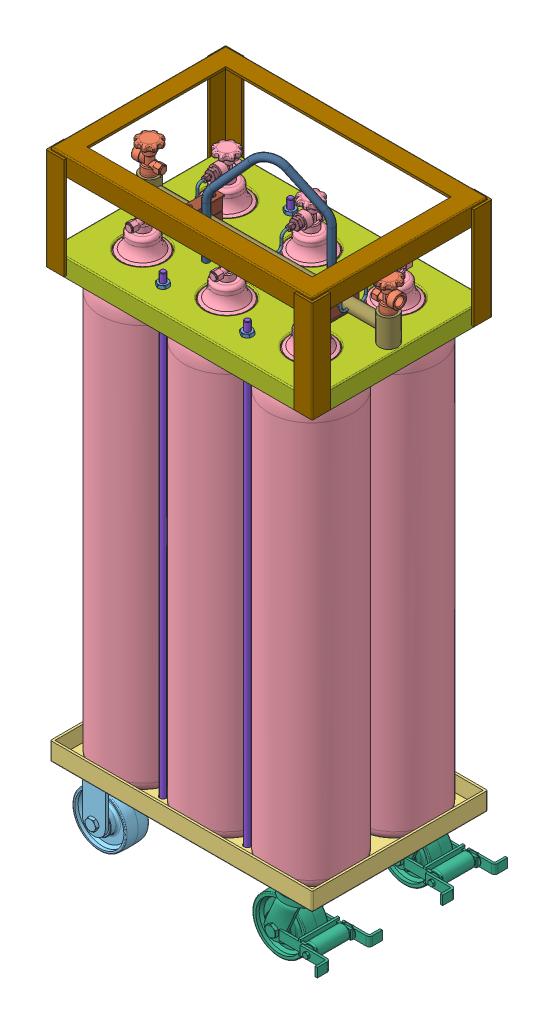
SolidWorks assembly GH2 6-Pack of K Bottles, configuration Default. Lengths in mm.
Overall size (889.45 1721.67 530.22).
43 component instances, 14 part files, 63 mates.
Components (placement in the parent):
- heavy hex jam nut_ai-1: heavy hex jam nut_ai [HHJNUT 0.6250-11-D-N] at (-117.475 1242.8474 177.8) x (1 0 0) z (0 1 0) size (26.97 31.15 9.68)
- heavy hex jam nut_ai-2: heavy hex jam nut_ai [HHJNUT 0.6250-11-D-N] at (117.475 1242.8474 177.8) x (1 0 0) z (0 1 0) size (26.97 31.15 9.68)
- heavy hex jam nut_ai-3: heavy hex jam nut_ai [HHJNUT 0.6250-11-D-N] at (117.475 1242.8474 -177.8) x (1 0 0) z (0 1 0) size (26.97 31.15 9.68)
- heavy hex jam nut_ai-4: heavy hex jam nut_ai [HHJNUT 0.6250-11-D-N] at (-117.475 1242.8474 -177.8) x (1 0 0) z (0 1 0) size (26.97 31.15 9.68)
- heavy hex jam nut_ai-5: heavy hex jam nut_ai [HHJNUT 0.6250-11-D-N] at (-117.475 -16.0274 177.8) x (1 0 0) z (0 -1 0) size (26.97 31.15 9.68)
- heavy hex jam nut_ai-6: heavy hex jam nut_ai [HHJNUT 0.6250-11-D-N] at (117.475 -16.0274 177.8) x (1 0 0) z (0 -1 0) size (26.97 31.15 9.68)
- heavy hex jam nut_ai-7: heavy hex jam nut_ai [HHJNUT 0.6250-11-D-N] at (117.475 -16.0274 -177.8) x (1 0 0) z (0 -1 0) size (26.97 31.15 9.68)
- heavy hex jam nut_ai-8: heavy hex jam nut_ai [HHJNUT 0.6250-11-D-N] at (-117.475 -16.0274 -177.8) x (1 0 0) z (0 -1 0) size (26.97 31.15 9.68)
- K Type Pressure Cylinder Valve-1: K Type Pressure Cylinder Valve [Default] at (333.375 -69.85 0) size (186.86 1361.63 197.95)
- Part15^GH2 6-Pack of K Bottles-1: Part15^GH2 6-Pack of K Bottles [Default] x (1 0 0) z (0 1 0) size (730.25 488.95 50.8) (virtual)
- K Type Pressure Cylinder GH2-1: K Type Pressure Cylinder GH2 [Default] at (234.95 -101.6 -117.475) x (0 0 1) z (-1 0 0) size (239.72 1361.76 239.72)
- K Type Pressure Cylinder GH2-5: K Type Pressure Cylinder GH2 [Default] at (234.95 -101.6 117.475) x (0 0 -1) z (1 0 0) size (239.72 1361.76 239.72)
- K Type Pressure Cylinder GH2-3: K Type Pressure Cylinder GH2 [Default] at (-234.95 -101.6 -117.475) x (0 0 1) z (-1 0 0) size (239.72 1361.76 239.72)
- K Type Pressure Cylinder GH2-4: K Type Pressure Cylinder GH2 [Default] at (-234.95 -101.6 117.475) x (0 0 -1) z (1 0 0) size (239.72 1361.76 239.72)
- K Type Pressure Cylinder GH2-2: K Type Pressure Cylinder GH2 [Default] at (0 -101.6 -117.475) x (0 0 1) z (-1 0 0) size (239.72 1361.76 239.72)
- K Type Pressure Cylinder GH2-6: K Type Pressure Cylinder GH2 [Default] at (0 -101.6 117.475) x (0 0 -1) z (1 0 0) size (239.72 1361.76 239.72)
- 2432T12_Extra-High-Capacity Viking Caster-1: 2432T12_Extra-High-Capacity Viking Caster [2432T12] at (-273.05 -123.825 168.275) x (1 0 0) z (0 1 0) size (158.75 127 193.67)
- 2432T55_Extra-High-Capacity Viking Caster-1: 2432T55_Extra-High-Capacity Viking Caster [2432T55] at (234.95 -123.825 174.625) x (1 0 0) z (0 1 0) size (241.3 180.97 193.67)
- 2432T55_Extra-High-Capacity Viking Caster-2: 2432T55_Extra-High-Capacity Viking Caster [2432T55] at (234.95 -123.825 -174.625) x (1 0 0) z (0 1 0) size (241.3 180.97 193.67)
- 2432T12_Extra-High-Capacity Viking Caster-2: 2432T12_Extra-High-Capacity Viking Caster [2432T12] at (-273.05 -123.825 -168.275) x (-1 0 0) z (0 1 0) size (158.75 127 193.67)
- Part16^GH2 6-Pack of K Bottles-1: Part16^GH2 6-Pack of K Bottles [Default] at (0 1226.82 0) x (-1 0 0) z (0 -1 0) size (730.25 488.95 50.8) (virtual)
- Part17^GH2 6-Pack of K Bottles-1: Part17^GH2 6-Pack of K Bottles [Default] at (117.475 1242.8474 177.8) x (1 0 0) z (0 1 0) size (15.88 15.88 1309.67) (virtual)
- Part17^GH2 6-Pack of K Bottles-2: Part17^GH2 6-Pack of K Bottles [Default] at (117.475 1242.8474 -177.8) x (1 0 0) z (0 1 0) size (15.88 15.88 1309.67) (virtual)
- Part17^GH2 6-Pack of K Bottles-3: Part17^GH2 6-Pack of K Bottles [Default] at (-117.475 1242.8474 177.8) x (1 0 0) z (0 1 0) size (15.88 15.88 1309.67) (virtual)
- Part17^GH2 6-Pack of K Bottles-4: Part17^GH2 6-Pack of K Bottles [Default] at (-117.475 1242.8474 -177.8) x (1 0 0) z (0 1 0) size (15.88 15.88 1309.67) (virtual)
- Part18^GH2 6-Pack of K Bottles-1: Part18^GH2 6-Pack of K Bottles [Default] at (0 1477.645 0) x (-1 0 0) z (0 -1 0) size (742.95 501.65 288.93) (virtual)
- Part19^GH2 6-Pack of K Bottles-1: Part19^GH2 6-Pack of K Bottles [Default] at (0 1233.17 0) x (1 0 0) z (0 1 0) size (254 133.35 288.47) (virtual)
- VIBRATION DAMPING CLAMPS-1: VIBRATION DAMPING CLAMPS [VD-1] at (190.5 1271.27 0) x (0 0 1) z (-1 0 0) size (101.6 80.96 31.75)
- VIBRATION DAMPING CLAMPS-2: VIBRATION DAMPING CLAMPS [VD-1] at (-190.5 1271.27 0) x (0 0 1) z (-1 0 0) size (101.6 80.96 31.75)
- K Type Pressure Cylinder Valve-2: K Type Pressure Cylinder Valve [Default] at (-333.375 -69.85 0) x (-1 0 0) z (0 0 -1) size (186.86 1361.63 197.95)
- Part20^GH2 6-Pack of K Bottles-1: Part20^GH2 6-Pack of K Bottles [Default] at (0 1233.17 0) x (1 0 0) z (0 1 0) size (717.55 50.8 76.2) (virtual)
- 0.250 Inch SL x 0.750 Inch NPT Adapter SS-400-1-12-1: 0.250 Inch SL x 0.750 Inch NPT Adapter SS-400-1-12 [Default] at (234.95 1314.45 -99.5858) x (0 0 1) z (-1 0 0) size (46.23 26.99 31.16)
- 0.250 Inch SL x 0.750 Inch NPT Adapter SS-400-1-12-2: 0.250 Inch SL x 0.750 Inch NPT Adapter SS-400-1-12 [Default] at (0 1314.45 -99.5858) x (0 0 1) z (-1 0 0) size (46.23 26.99 31.16)
- 0.250 Inch SL x 0.750 Inch NPT Adapter SS-400-1-12-3: 0.250 Inch SL x 0.750 Inch NPT Adapter SS-400-1-12 [Default] at (-234.95 1314.45 -99.5858) x (0 0 1) z (-1 0 0) size (46.23 26.99 31.16)
- 0.250 Inch SL x 0.750 Inch NPT Adapter SS-400-1-12-4: 0.250 Inch SL x 0.750 Inch NPT Adapter SS-400-1-12 [Default] at (234.95 1314.45 99.5858) x (0 0 -1) z (1 0 0) size (46.23 26.99 31.16)
- 0.250 Inch SL x 0.750 Inch NPT Adapter SS-400-1-12-5: 0.250 Inch SL x 0.750 Inch NPT Adapter SS-400-1-12 [Default] at (0 1314.45 99.5858) x (0 0 -1) z (1 0 0) size (46.23 26.99 31.16)
- 0.250 Inch SL x 0.750 Inch NPT Adapter SS-400-1-12-6: 0.250 Inch SL x 0.750 Inch NPT Adapter SS-400-1-12 [Default] at (-234.95 1314.45 99.5858) x (0 0 -1) z (1 0 0) size (46.23 26.99 31.16)
- Part21^GH2 6-Pack of K Bottles-1: Part21^GH2 6-Pack of K Bottles [Default] at (234.95 1314.45 -68.5978) size (6.35 49.53 68.6) (virtual)
- Part21^GH2 6-Pack of K Bottles-2: Part21^GH2 6-Pack of K Bottles [Default] at (0 1314.45 -68.5978) size (6.35 49.53 68.6) (virtual)
- Part21^GH2 6-Pack of K Bottles-3: Part21^GH2 6-Pack of K Bottles [Default] at (-234.95 1314.45 -68.5978) size (6.35 49.53 68.6) (virtual)
- Part21^GH2 6-Pack of K Bottles-4: Part21^GH2 6-Pack of K Bottles [Default] at (234.95 1314.45 68.5978) x (-1 0 0) z (0 0 -1) size (6.35 49.53 68.6) (virtual)
- Part21^GH2 6-Pack of K Bottles-5: Part21^GH2 6-Pack of K Bottles [Default] at (0 1314.45 68.5978) x (-1 0 0) z (0 0 -1) size (6.35 49.53 68.6) (virtual)
- Part21^GH2 6-Pack of K Bottles-6: Part21^GH2 6-Pack of K Bottles [Default] at (-234.95 1314.45 68.5978) x (-1 0 0) z (0 0 -1) size (6.35 49.53 68.6) (virtual)
Mates (geometry in assembly coordinates):
- Parallel2: parallel aligned: plane of K Type Pressure Cylinder GH2-1 through (234.95 1314.45 -85.725) normal (0 0 1)
- Coincident3: coincident anti-aligned: plane of K Type Pressure Cylinder GH2-1 through (234.95 0 -117.475) normal (0 -1 0)
- Distance2: distance = 117.475 mm aligned: plane of K Type Pressure Cylinder GH2-1 through (234.95 -101.6 -117.475) normal (0 0 1)
- Distance3: distance = 234.95 mm anti-aligned: plane of K Type Pressure Cylinder GH2-1 through (234.95 -101.6 -117.475) normal (-1 0 0)
- InPlace1: in place: plane of Part15^GH2 6-Pack of K Bottles-1 through (0 0 0) normal (0 1 0); moOrthogonalPlaneRef_w of Part15^GH2 6-Pack of K Bottles-1 through (0 0 0) normal (0 0 -1); plane of Part15^GH2 6-Pack of K Bottles-1 through (0 0 0) normal (1 0 0); unknown of Part15^GH2 6-Pack of K Bottles-1
- Coincident6: coincident aligned: 
- Coincident7: coincident aligned: plane of Part15^Assem5-1 through (0 0 0) normal (0 0 -1)
- Coincident8: coincident anti-aligned: plane of Part15^Assem5-1 through (0 0 0) normal (1 0 0)
- Coincident9: coincident anti-aligned: plane of Part15^Assem5-1 through (0 -6.35 0) normal (0 -1 0); plane of 2432T12_Extra-High-Capacity Viking Caster-1 through (-352.425 -6.35 231.775) normal (0 1 0)
- Distance4: distance = 12.7 mm aligned: plane of 2432T12_Extra-High-Capacity Viking Caster-1 through (-352.425 -6.35 231.775) normal (-1 0 0); plane of Part15^Assem5-1 through (-365.125 -6.35 244.475) normal (-1 0 0)
- Distance5: distance = 12.7 mm aligned: plane of 2432T12_Extra-High-Capacity Viking Caster-1 through (-352.425 -15.875 231.775) normal (0 0 1); plane of Part15^Assem5-1 through (-365.125 -6.35 244.475) normal (0 0 1)
- Distance6: distance = 12.7 mm aligned: plane of 2432T55_Extra-High-Capacity Viking Caster-1 through (193.675 -12.7 231.775) normal (0 0 1); plane of Part15^Assem5-1 through (-365.125 -6.35 244.475) normal (0 0 1)
- Coincident13: coincident anti-aligned: plane of Part15^Assem5-1 through (0 -6.35 0) normal (0 -1 0); plane of 2432T55_Extra-High-Capacity Viking Caster-1 through (193.675 -6.35 231.775) normal (0 1 0)
- Distance7: distance = 12.7 mm aligned: plane of 2432T55_Extra-High-Capacity Viking Caster-1 through (352.425 -6.35 231.775) normal (1 0 0); plane of Part15^Assem5-1 through (365.125 -6.35 244.475) normal (1 0 0)
- InPlace2: in place: plane of Part16^GH2 6-Pack of K Bottles-1 through (0 1226.82 0) normal (0 -1 0); plane of Part16^GH2 6-Pack of K Bottles-1 through (0 1226.82 0) normal (0 0 -1); plane of Part16^GH2 6-Pack of K Bottles-1 through (0 1226.82 0) normal (-1 0 0); unknown of Part16^GH2 6-Pack of K Bottles-1
- Coincident15: coincident aligned: 
- Coincident16: coincident aligned: plane of Part16^Assem5-1 through (0 1226.82 0) normal (0 0 -1)
- Coincident17: coincident anti-aligned: plane of Part16^Assem5-1 through (0 1226.82 0) normal (-1 0 0)
- Concentric1: concentric aligned: cylinder of Part16^Assem5-1 through (-117.475 1182.37 177.8) axis (0 1 0) radius 9.525; cylinder of heavy hex jam nut_ai-1 through (-117.475 1217.8099 177.8) axis (0 1 0) radius 7.9375
- Coincident18: coincident anti-aligned: plane of Part16^Assem5-1 through (0 1233.17 0) normal (0 1 0); plane of heavy hex jam nut_ai-1 through (-144.4498 1233.17 177.8) normal (0 -1 0)
- Concentric2: concentric aligned: cylinder of Part16^Assem5-1 through (117.475 1182.37 177.8) axis (0 1 0) radius 9.525; cylinder of heavy hex jam nut_ai-2 through (117.475 1217.8099 177.8) axis (0 1 0) radius 7.9375
- Coincident19: coincident anti-aligned: plane of Part16^Assem5-1 through (0 1233.17 0) normal (0 1 0); plane of heavy hex jam nut_ai-2 through (90.5002 1233.17 177.8) normal (0 -1 0)
- Concentric3: concentric aligned: cylinder of Part16^Assem5-1 through (117.475 1182.37 -177.8) axis (0 1 0) radius 9.525; cylinder of heavy hex jam nut_ai-3 through (117.475 1217.8099 -177.8) axis (0 1 0) radius 7.9375
- Coincident20: coincident anti-aligned: plane of Part16^Assem5-1 through (0 1233.17 0) normal (0 1 0); plane of heavy hex jam nut_ai-3 through (90.5002 1233.17 -177.8) normal (0 -1 0)
- Concentric4: concentric aligned: cylinder of Part16^Assem5-1 through (-117.475 1182.37 -177.8) axis (0 1 0) radius 9.525; cylinder of heavy hex jam nut_ai-4 through (-117.475 1217.8099 -177.8) axis (0 1 0) radius 7.9375
- Coincident21: coincident anti-aligned: plane of Part16^Assem5-1 through (0 1233.17 0) normal (0 1 0); plane of heavy hex jam nut_ai-4 through (-144.4498 1233.17 -177.8) normal (0 -1 0)
- Concentric5: concentric anti-aligned: cylinder of Part15^Assem5-1 through (-117.475 -6.35 177.8) axis (0 1 0) radius 9.525; cylinder of heavy hex jam nut_ai-5 through (-117.475 9.0101 177.8) axis (0 -1 0) radius 7.9375
- Coincident22: coincident anti-aligned: plane of Part15^Assem5-1 through (0 -6.35 0) normal (0 -1 0); plane of heavy hex jam nut_ai-5 through (-144.4498 -6.35 177.8) normal (0 1 0)
- Concentric6: concentric anti-aligned: cylinder of Part15^Assem5-1 through (117.475 -6.35 177.8) axis (0 1 0) radius 9.525; cylinder of heavy hex jam nut_ai-6 through (117.475 9.0101 177.8) axis (0 -1 0) radius 7.9375
- Coincident23: coincident anti-aligned: plane of Part15^Assem5-1 through (0 -6.35 0) normal (0 -1 0); plane of heavy hex jam nut_ai-6 through (90.5002 -6.35 177.8) normal (0 1 0)
- Concentric7: concentric anti-aligned: cylinder of Part15^Assem5-1 through (117.475 -6.35 -177.8) axis (0 1 0) radius 9.525; cylinder of heavy hex jam nut_ai-7 through (117.475 9.0101 -177.8) axis (0 -1 0) radius 7.9375
- Coincident24: coincident anti-aligned: plane of Part15^Assem5-1 through (0 -6.35 0) normal (0 -1 0); plane of heavy hex jam nut_ai-7 through (90.5002 -6.35 -177.8) normal (0 1 0)
- Concentric8: concentric anti-aligned: cylinder of Part15^Assem5-1 through (-117.475 -6.35 -177.8) axis (0 1 0) radius 9.525; cylinder of heavy hex jam nut_ai-8 through (-117.475 9.0101 -177.8) axis (0 -1 0) radius 7.9375
- Coincident25: coincident anti-aligned: plane of Part15^Assem5-1 through (0 -6.35 0) normal (0 -1 0); plane of heavy hex jam nut_ai-8 through (-144.4498 -6.35 -177.8) normal (0 1 0)
- InPlace3: in place: plane of ? through (90.5002 1242.8474 177.8) normal (0 1 0); plane of ? through (0 1242.8474 0) normal (0 1 0); plane of ? through (90.5002 1242.8474 177.8) normal (0 1 0); plane of ? through (0 1242.8474 0) normal (0 0 -1); plane of ? through (90.5002 1242.8474 177.8) normal (0 1 0); plane of ? through (0 1242.8474 0) normal (1 0 0); plane of ? through (90.5002 1242.8474 177.8) normal (0 1 0); unknown of ?
- Coincident26: coincident aligned: plane of ?; plane of ?
- Coincident27: coincident aligned: moOrthogonalPlaneRef_w of heavy hex jam nut_ai-2 through (117.475 1242.8474 177.8) normal (0 0 -1); plane of Part17^Assem5-1 through (117.475 1242.8474 177.8) normal (0 0 -1)
- Coincident28: coincident anti-aligned: moOrthogonalPlaneRef_w of heavy hex jam nut_ai-2 through (117.475 1242.8474 177.8) normal (-1 0 0); plane of Part17^Assem5-1 through (117.475 1242.8474 177.8) normal (1 0 0)
- InPlace4: in place: plane of Part18^GH2 6-Pack of K Bottles-1 through (0 1477.645 0) normal (0 -1 0); plane of Part18^GH2 6-Pack of K Bottles-1 through (0 1477.645 0) normal (0 0 -1); plane of Part18^GH2 6-Pack of K Bottles-1 through (0 1477.645 0) normal (-1 0 0); unknown of Part18^GH2 6-Pack of K Bottles-1
- Coincident29: coincident aligned: 
- Coincident30: coincident aligned: plane of Part18^GHe 6-Pack of K Bottles-1 through (0 1477.645 0) normal (0 0 -1)
- Coincident31: coincident anti-aligned: plane of Part18^GHe 6-Pack of K Bottles-1 through (0 1477.645 0) normal (-1 0 0)
- InPlace5: in place: plane of Part16^GH2 6-Pack of K Bottles-1 through (0 1233.17 0) normal (0 1 0); plane of ? through (0 1233.17 0) normal (0 1 0); plane of Part16^GH2 6-Pack of K Bottles-1 through (0 1233.17 0) normal (0 1 0); plane of ? through (0 1233.17 0) normal (0 0 -1); plane of Part16^GH2 6-Pack of K Bottles-1 through (0 1233.17 0) normal (0 1 0); plane of ? through (0 1233.17 0) normal (1 0 0); plane of Part16^GH2 6-Pack of K Bottles-1 through (0 1233.17 0) normal (0 1 0); unknown of ?
- Coincident32: coincident aligned: plane of ?; plane of ?
- Coincident33: coincident aligned: moOrthogonalPlaneRef_w of Part16^GHe 6-Pack of K Bottles-1 through (0 1233.17 0) normal (0 0 -1); plane of Part19^GHe 6-Pack of K Bottles-1 through (0 1233.17 0) normal (0 0 -1)
- Coincident34: coincident anti-aligned: moOrthogonalPlaneRef_w of Part16^GHe 6-Pack of K Bottles-1 through (0 1233.17 0) normal (-1 0 0); plane of Part19^GHe 6-Pack of K Bottles-1 through (0 1233.17 0) normal (1 0 0)
- Coincident35: coincident anti-aligned: plane of Part16^GHe 6-Pack of K Bottles-1 through (0 1233.17 0) normal (0 1 0); plane of VIBRATION DAMPING CLAMPS-1 through (190.5 1233.17 0) normal (0 -1 0)
- Coincident36: coincident aligned: plane of VIBRATION DAMPING CLAMPS-1 through (190.5 1271.27 0) normal (0 0 1)
- Distance8: distance = 190.5 mm: plane of assembly through (0 0 0) normal (1 0 0); plane of assembly; plane of VIBRATION DAMPING CLAMPS-1 through (190.5 1271.27 0) normal (-1 0 0)
- Coincident38: coincident anti-aligned: plane of Part18^GHe 6-Pack of K Bottles-1 through (365.125 1110.528 200.025) normal (-1 0 0); plane of K Type Pressure Cylinder Valve-1 through (365.125 1346.2 0) normal (1 0 0)
- Coincident39: coincident aligned: plane of K Type Pressure Cylinder Valve-1 through (333.375 -69.85 0) normal (0 0 1)
- Distance9: distance = 31.75 mm aligned: plane of K Type Pressure Cylinder GH2-5 through (234.95 1361.0395 117.475) normal (0 1 0); plane of K Type Pressure Cylinder Valve-1 through (333.375 1392.7895 0) normal (0 1 0)
- InPlace6: in place: plane of Part16^GH2 6-Pack of K Bottles-1 through (0 1233.17 0) normal (0 1 0); plane of ? through (0 1233.17 0) normal (0 1 0); plane of Part16^GH2 6-Pack of K Bottles-1 through (0 1233.17 0) normal (0 1 0); plane of ? through (0 1233.17 0) normal (0 0 -1); plane of Part16^GH2 6-Pack of K Bottles-1 through (0 1233.17 0) normal (0 1 0); plane of ? through (0 1233.17 0) normal (1 0 0); plane of Part16^GH2 6-Pack of K Bottles-1 through (0 1233.17 0) normal (0 1 0); unknown of ?
- Coincident41: coincident aligned: plane of ?; plane of ?
- Coincident42: coincident aligned: moOrthogonalPlaneRef_w of Part16^GHe 6-Pack of K Bottles-1 through (0 1233.17 0) normal (0 0 -1); plane of Part20^GHe 6-Pack of K Bottles-1 through (0 1233.17 0) normal (0 0 -1)
- Coincident43: coincident anti-aligned: moOrthogonalPlaneRef_w of Part16^GHe 6-Pack of K Bottles-1 through (0 1233.17 0) normal (-1 0 0); plane of Part20^GHe 6-Pack of K Bottles-1 through (0 1233.17 0) normal (1 0 0)
- Concentric9: concentric aligned: cylinder of K Type Pressure Cylinder GH2-1 through (234.95 1314.45 -85.725) axis (0 0 1) radius 12.1666; cylinder of 0.250 Inch SL x 0.750 Inch NPT Adapter SS-400-1-12-1 through (234.95 1314.45 -82.5779) axis (0 0 1) radius 13.335
- Parallel3: parallel aligned: plane of K Type Pressure Cylinder GH2-1 through (234.95 1361.0395 -117.475) normal (0 1 0); plane of 0.250 Inch SL x 0.750 Inch NPT Adapter SS-400-1-12-1 through (234.95 1327.9437 -79.4309) normal (0 1 0)
- Coincident45: coincident aligned: plane of K Type Pressure Cylinder GH2-1 through (234.95 1314.45 -85.725) normal (0 0 1); circle of 0.250 Inch SL x 0.750 Inch NPT Adapter SS-400-1-12-1
- InPlace7: in place: plane of 0.250 Inch SL x 0.750 Inch NPT Adapter SS-400-1-12-1 through (234.95 1314.45 -68.5978) normal (0 0 1); plane of ? through (0 0 -68.5978) normal (0 0 1); plane of 0.250 Inch SL x 0.750 Inch NPT Adapter SS-400-1-12-1 through (234.95 1314.45 -68.5978) normal (0 0 1); plane of ? through (0 0 -68.5978) normal (0 1 0); plane of 0.250 Inch SL x 0.750 Inch NPT Adapter SS-400-1-12-1 through (234.95 1314.45 -68.5978) normal (0 0 1); plane of ? through (0 0 -68.5978) normal (1 0 0); plane of 0.250 Inch SL x 0.750 Inch NPT Adapter SS-400-1-12-1 through (234.95 1314.45 -68.5978) normal (0 0 1); unknown of Part21^GH2 6-Pack of K Bottles-1
- Coincident46: coincident aligned: plane of ?; plane of ?
- Coincident47: coincident aligned: moOrthogonalPlaneRef_w of 0.250 Inch SL x 0.750 Inch NPT Adapter SS-400-1-12-1 through (234.95 1314.45 -68.5978) normal (0 1 0); plane of Part21^GHe 6-Pack of K Bottles-1 through (234.95 1314.45 -68.5978) normal (0 1 0)
- Coincident48: coincident anti-aligned: moOrthogonalPlaneRef_w of 0.250 Inch SL x 0.750 Inch NPT Adapter SS-400-1-12-1 through (234.95 1314.45 -68.5978) normal (-1 0 0); plane of Part21^GHe 6-Pack of K Bottles-1 through (234.95 1314.45 -68.5978) normal (1 0 0)
